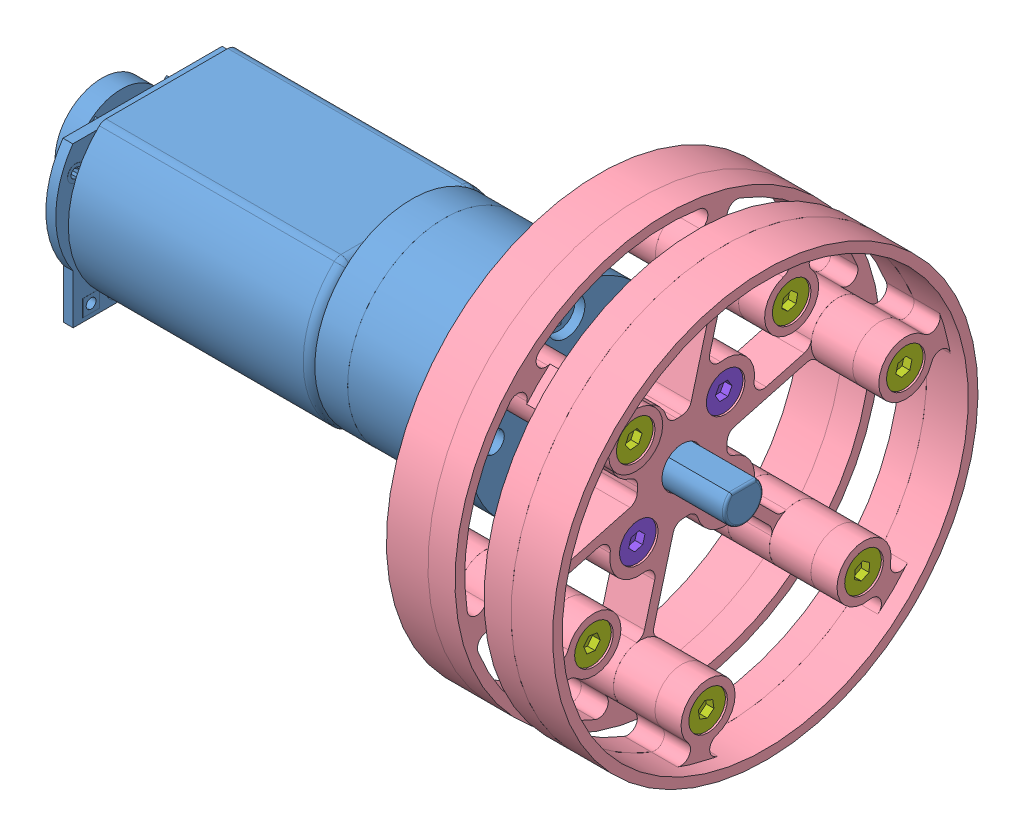
SolidWorks assembly driven-wheel, configuration Default. Lengths in mm.
Overall size (69.7 73.35 73.35).
30 component instances, 8 part files, 12 mates.
Components (placement in the parent):
- motor-with-encoder-1: motor-with-encoder [Default] at origin size (67.5 20.82 20.4)
- motor-hub-1: motor-hub [Default] at (8 0 0) x (0 0 1) z (0 -1 0) size (15.85 19.2 30.98)
- scrub-scew-m2.5-6mm-1: scrub-scew-m2.5-6mm [Default] at (6 1.5 0) x (0.030675 0 -0.999529) z (0.999529 0 0.030675) size (2.5 6 2.5)
- wheel-powered-1: wheel-powered [Default] at (7.7 0 0) x (0 0.707107 -0.707107) z (0 -0.707107 -0.707107) size (60.11 17.2 60.11)
  - wheel-1: wheel [Powered middle mount] at origin size (44 4.3 44)
  - wheel-2: wheel [Powered inner] at (0 -4.3 0) size (44 4.3 44)
  - insert-m2-4mm-1: insert-m2-4mm [Default] at (-14.4626 2.8 -8.35) size (3.2 3 3.18)
  - insert-m2-4mm-2: insert-m2-4mm [Default] at (0 2.8 -16.7) x (0.982082 0 -0.188455) z (0.188455 0 0.982082) size (3.2 3 3.18)
  - insert-m2-4mm-3: insert-m2-4mm [Default] at (14.4626 2.8 -8.35) x (0.918365 0 -0.395734) z (0.395734 0 0.918365) size (3.2 3 3.18)
  - insert-m2-4mm-4: insert-m2-4mm [Default] at (14.4626 2.8 8.35) x (0.8 0 -0.6) z (0.6 0 0.8) size (3.2 3 3.18)
  - insert-m2-4mm-5: insert-m2-4mm [Default] at (0 2.8 16.7) x (0.63358 0 -0.773678) z (0.773678 0 0.63358) size (3.2 3 3.18)
  - insert-m2-4mm-6: insert-m2-4mm [Default] at (-14.4626 2.8 8.35) x (0.443629 0 -0.896211) z (0.896211 0 0.443629) size (3.2 3 3.18)
  - countersunk-screw-m2-6mm-1: countersunk-screw-m2-6mm [Default] at (-14.4626 -4.1 8.35) x (0 1 0) z (0 0 1) size (6 4 4)
  - countersunk-screw-m2-6mm-2: countersunk-screw-m2-6mm [Default] at (0 -4.1 16.7) x (0 1 0) z (0.188455 0 0.982082) size (6 4 4)
  - countersunk-screw-m2-6mm-4: countersunk-screw-m2-6mm [Default] at (14.4626 -4.1 8.35) x (0 1 0) z (0.395734 0 0.918365) size (6 4 4)
  - countersunk-screw-m2-6mm-6: countersunk-screw-m2-6mm [Default] at (14.4626 -4.1 -8.35) x (0 1 0) z (0.6 0 0.8) size (6 4 4)
  - countersunk-screw-m2-6mm-8: countersunk-screw-m2-6mm [Default] at (0 -4.1 -16.7) x (0 1 0) z (0.773678 0 0.63358) size (6 4 4)
  - countersunk-screw-m2-6mm-10: countersunk-screw-m2-6mm [Default] at (-14.4626 -4.1 -8.35) x (0 1 0) z (0.896211 0 0.443629) size (6 4 4)
  - wheel-3: wheel [Free middle] at (0 8.6 0) x (-0.5 0 -0.866025) z (-0.866025 0 0.5) size (44 4.3 44)
  - wheel-4: wheel [Free outer] at (0 8.6 0) size (44 4.3 44)
  - countersunk-screw-m2-10mm-1: countersunk-screw-m2-10mm [Default] at (14.4626 11.1 8.35) x (0 -1 0) z (0 0 1) size (10 4 4)
  - countersunk-screw-m2-10mm-2: countersunk-screw-m2-10mm [Default] at (0 11.1 16.7) x (0 -1 0) z (0.188455 0 0.982082) size (10 4 4)
  - countersunk-screw-m2-10mm-4: countersunk-screw-m2-10mm [Default] at (-14.4626 11.1 8.35) x (0 -1 0) z (0.395734 0 0.918365) size (10 4 4)
  - countersunk-screw-m2-10mm-6: countersunk-screw-m2-10mm [Default] at (-14.4626 11.1 -8.35) x (0 -1 0) z (0.6 0 0.8) size (10 4 4)
  - countersunk-screw-m2-10mm-8: countersunk-screw-m2-10mm [Default] at (0 11.1 -16.7) x (0 -1 0) z (0.773678 0 0.63358) size (10 4 4)
  - countersunk-screw-m2-10mm-10: countersunk-screw-m2-10mm [Default] at (14.4626 11.1 -8.35) x (0 -1 0) z (0.896211 0 0.443629) size (10 4 4)
- countersunk-screw-m2-8mm-1: countersunk-screw-m2-8mm [Default] at (11.8 4.4901 4.4901) x (-1 0 0) z (0 0.924225 0.381849) size (8 4 4)
- countersunk-screw-m2-8mm-2: countersunk-screw-m2-8mm [Default] at (11.8 4.4901 -4.4901) x (-1 0 0) z (0 0.85199 0.523557) size (8 4 4)
- countersunk-screw-m2-8mm-4: countersunk-screw-m2-8mm [Default] at (11.8 -4.4901 -4.4901) x (-1 0 0) z (0 0.77839 0.627782) size (8 4 4)
- countersunk-screw-m2-8mm-6: countersunk-screw-m2-8mm [Default] at (11.8 -4.4901 4.4901) x (-1 0 0) z (0 0.716484 0.697604) size (8 4 4)
Mates (geometry in assembly coordinates):
- Concentric1: concentric: cylinder of motor-with-encoder-1 through (18.4 0 0) axis (-1 0 0) radius 2; cylinder of motor-hub-1 through (4 0 0) axis (1 0 0) radius 2.025
- Parallel1: parallel: plane of motor-with-encoder-1 through (0.3074 1.5 0) normal (0 1 0); plane of motor-hub-1 through (4 1.425 0) normal (0 -1 0)
- Concentric2: concentric: cylinder of motor-hub-1 through (6 -7.4911 0) axis (0 -1 0) radius 1.05; cylinder of scrub-scew-m2.5-6mm-1 through (6 7.5 0) axis (0 -1 0) radius 1.25
- Coincident2: coincident: plane of motor-with-encoder-1 through (0.3074 1.5 0) normal (0 1 0); plane of scrub-scew-m2.5-6mm-1 through (6 1.5 0) normal (0 -1 0)
- Concentric3: concentric: cylinder of motor-hub-1 through (4 -4.4901 4.4901) axis (1 0 0) radius 0.85; cylinder of wheel-powered-1/wheel-1 through (7.699 -4.4901 4.4901) axis (1 0 0) radius 1.1
- Concentric4: concentric: cylinder of motor-hub-1 through (4 4.4901 -4.4901) axis (1 0 0) radius 0.85; cylinder of wheel-powered-1/wheel-1 through (7.699 4.4901 -4.4901) axis (1 0 0) radius 1.1
- Coincident9: coincident: plane of motor-hub-1 through (8 0 0) normal (1 0 0); plane of wheel-powered-1/wheel-1 through (8 0 0) normal (-1 0 0)
- Coincident10: coincident: plane of motor-with-encoder-1 through (4 0 0) normal (1 0 0); plane of motor-hub-1 through (4 0 0) normal (-1 0 0)
- Coincident15: coincident: cone of wheel-powered-1/wheel-1 through (11.7 4.4901 4.4901) axis (-1 0 0); cone of countersunk-screw-m2-8mm-1 through (10.7 4.4901 4.4901) axis (-1 0 0)
- Coincident16: coincident: cone of wheel-powered-1/wheel-1 through (11.7 4.4901 -4.4901) axis (-1 0 0); cone of countersunk-screw-m2-8mm-2 through (10.7 4.4901 -4.4901) axis (-1 0 0)
- Coincident17: coincident: cone of wheel-powered-1/wheel-1 through (11.7 -4.4901 -4.4901) axis (-1 0 0); cone of countersunk-screw-m2-8mm-4 through (10.7 -4.4901 -4.4901) axis (-1 0 0)
- Coincident18: coincident: cone of wheel-powered-1/wheel-1 through (11.7 -4.4901 4.4901) axis (-1 0 0); cone of countersunk-screw-m2-8mm-6 through (10.7 -4.4901 4.4901) axis (-1 0 0)
